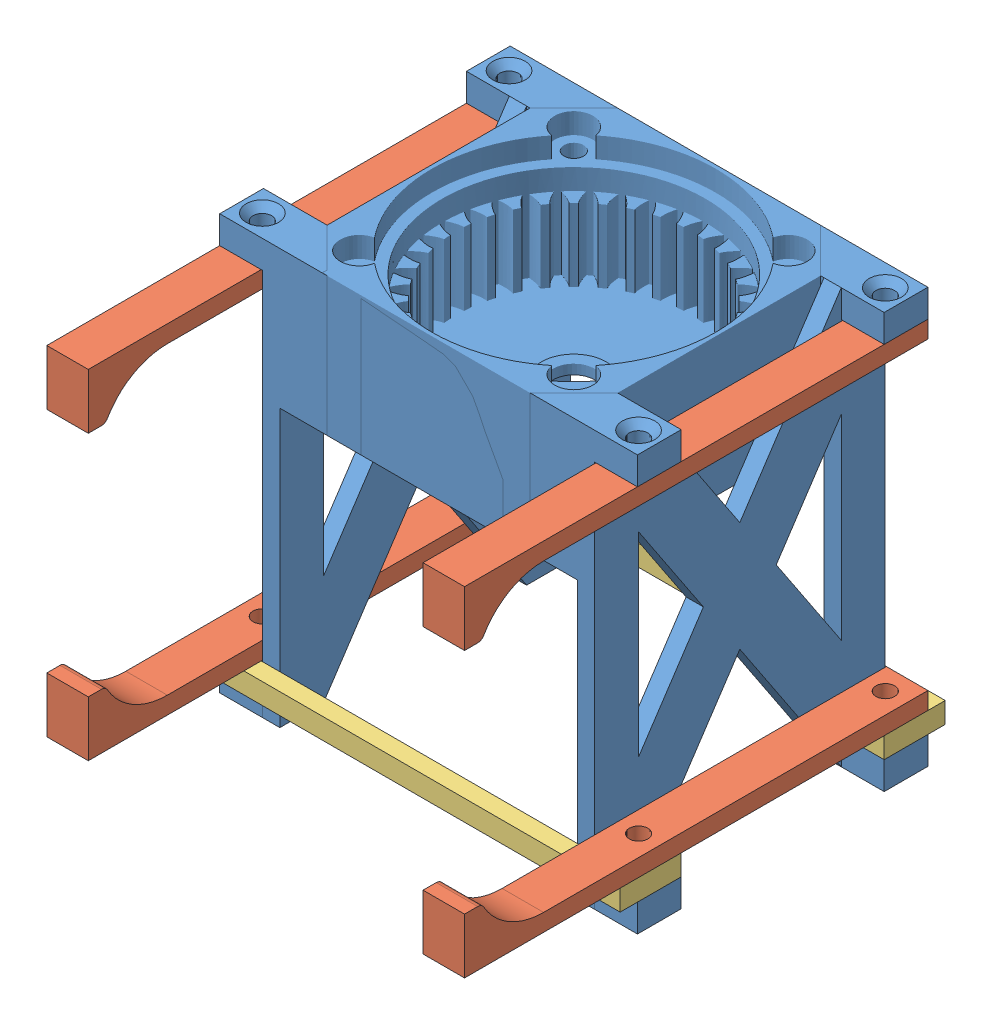
SolidWorks assembly Sestava1, configuration Výchozí. Lengths in mm.
Overall size (60.4 75.47 69.5).
7 component instances, 3 part files, 18 mates.
Components (placement in the parent):
- Base-1: Base [Výchozí] at (-6.5855 -23.2057 63.4102) size (60.4 75.47 42)
- leg-1: leg [Výchozí] at (17.6145 24.9943 42.4106) x (-1 0 0) z (0 -1 0) size (6 67 8)
- leg-3: leg [Výchozí] at (-36.7855 24.9943 42.4097) x (-1 0 0) z (0 -1 0) size (6 67 8)
- support-1: support [Výchozí] at (23.6145 -24.0057 86.9097) x (0 1 0) z (0 0 -1) size (3 60.4 8.83)
- support-2: support [Výchozí] at (23.6145 -27.0057 39.9106) x (0 -1 0) z (0 0 1) size (3 60.4 8.83)
- leg-6: leg [Výchozí] at (-30.7855 -24.0057 42.4106) x (1 0 0) z (0 1 0) size (6 67 8)
- leg-7: leg [Výchozí] at (23.6145 -24.0057 42.4097) x (1 0 0) z (0 1 0) size (6 67 8)
Mates (geometry in assembly coordinates):
- Sjednocená17: coincident anti-aligned: circle of Base-1; circle of leg-1
- Sjednocená18: coincident aligned: circle of Base-1; circle of leg-1
- Sjednocená19: coincident anti-aligned: plane of Base-1 through (-6.5855 24.9943 63.4102) normal (0 -1 0); plane of leg-1 through (17.6145 24.9943 42.4106) normal (0 1 0)
- Soustředná9: concentric anti-aligned: circle of Base-1; circle of leg-3
- Soustředná10: concentric aligned: circle of Base-1; circle of leg-3
- Sjednocená23: coincident anti-aligned: plane of Base-1 through (-6.5855 24.9943 63.4102) normal (0 -1 0); plane of leg-3 through (-36.7855 24.9943 42.4097) normal (0 1 0)
- Sjednocená26: coincident anti-aligned: plane of support-2 through (23.6145 -24.0057 42.4106) normal (0 1 0); plane of leg-7 through (23.6145 -24.0057 42.4097) normal (0 -1 0)
- Soustředná16: concentric aligned: circle of support-2; circle of leg-7
- Soustředná17: concentric aligned: circle of support-1; circle of leg-7
- Sjednocená27: coincident anti-aligned: plane of support-2 through (23.6145 -24.0057 42.4106) normal (0 1 0); plane of leg-6 through (-30.7855 -24.0057 42.4106) normal (0 -1 0)
- Sjednocená28: coincident aligned: circle of support-2; circle of leg-6
- Sjednocená29: coincident aligned: circle of support-1; circle of leg-6
- Sjednocená30: coincident anti-aligned: circle of Base-1; circle of support-2
- Soustředná18: concentric anti-aligned: circle of Base-1; circle of support-1
- Soustředná19: concentric anti-aligned: circle of Base-1; circle of support-2
- Soustředná20: concentric anti-aligned: circle of Base-1; circle of support-1
- Soustředná21: concentric aligned: circle of Base-1; circle of leg-1
- Soustředná22: concentric anti-aligned: circle of Base-1; circle of leg-1
